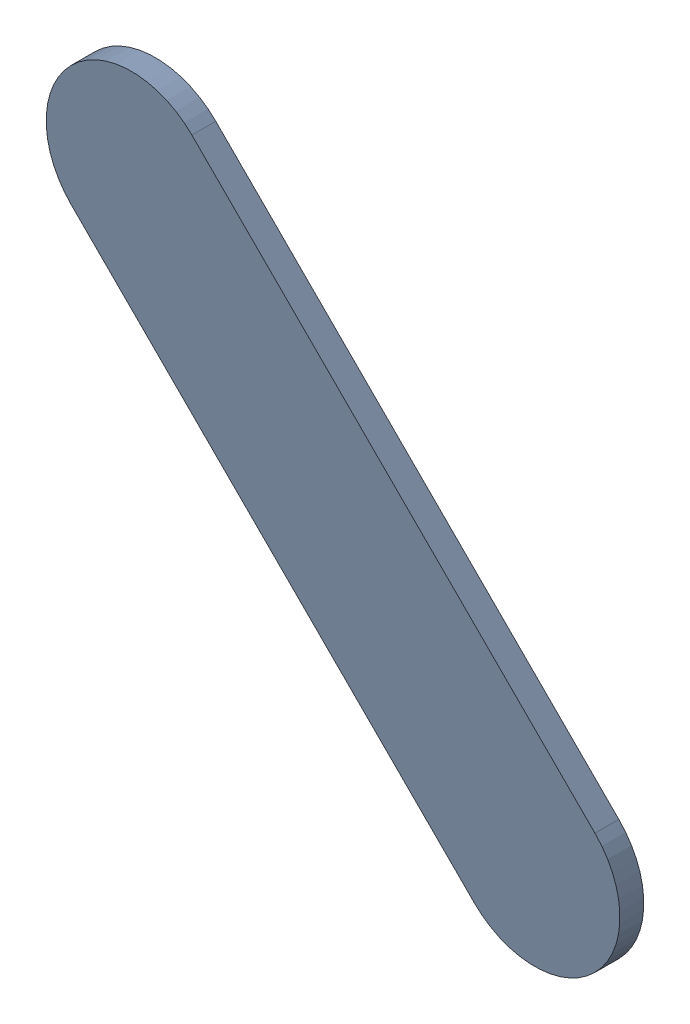
SolidWorks assembly Track (22.2mm,53.3mm)(22.8mm,52.7mm) on Top Layer, configuration Predeterminado. Lengths in mm.
Overall size (0.85 0.85 0.04).
2 component instances, 1 part files, 0 mates.
Components (placement in the parent):
- Track (22.2mm,53.3mm)(22.8mm,52.7mm) on Top Layer-1-1: Track (22.2mm,53.3mm)(22.8mm,52.7mm) on Top Layer-1 [Predeterminado] at (-68.317 -44.187 -0.0457) size (0.85 0.85 0.04)
  - Track (22.2mm,53.3mm)(22.8mm,52.7mm) on Top Layer-Part-1-1: Track (22.2mm,53.3mm)(22.8mm,52.7mm) on Top Layer-Part-1 [Predeterminado] at origin size (0.85 0.85 0.04)
